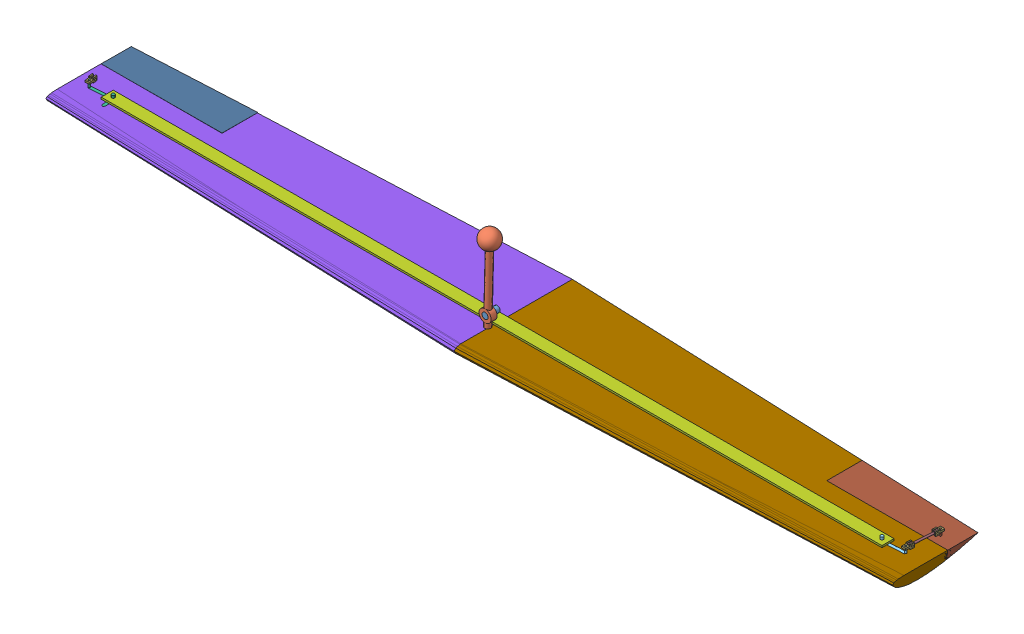
SolidWorks assembly ilk montaj, configuration Varsayılan. Lengths in mm.
Overall size (1400.06 167.48 195.35).
16 component instances, 13 part files, 37 mates.
Components (placement in the parent):
- 1 parça-1: 1 parça [Varsayılan] at (-40.5171 -15.683 10) size (10 10 20)
- ağırlık-1: ağırlık [Varsayılan] at (-40.5171 -15.683 20) x (-0.999712 0.024004 0) z (0 0 1) size (30 159 30)
- acrefour parça-1: acrefour parça [Varsayılan] at (-60.7392 -45.724 23.5) x (-0.999997 -0.002545 0) z (0 0 1) size (50 6 9)
- kanat uzatma-1: kanat uzatma [Varsayılan] at (-70.2401 -44.5815 25) x (0 0 -1) z (0.999997 0.002545 0) size (7 7 620)
- kanat uzatma-2: kanat uzatma [Varsayılan] at (-12.2403 -44.4339 25) x (0 0 1) z (-0.999997 -0.002545 0) size (7 7 620)
- sağ L-1: sağ L [Varsayılan] at (571.2051 -32.1155 16.2863) x (0.998401 0.002541 -0.05647) z (0.002545 -0.999997 0) size (41.5 21.5 23)
- sol L-1: sol L [Varsayılan] at (-694.806 -35.3378 16.0044) x (0.998401 0.002541 -0.05647) z (0.002545 -0.999997 0) size (41.5 21.5 23)
- baz-1: baz [Varsayılan] at (-442.2566 -34.695 7.4933) x (0.999997 0.002545 0) z (-0.002545 0.999997 0) size (1291 20 5)
- sol kanat-1: sol kanat [Varsayılan] at (-38.6126 -72.1334 -489.2786) x (0 0 -1) z (-0.999997 -0.002545 0) size (195.35 23.39 700)
- sağ kanat-1: sağ kanat [Varsayılan] at (-58.6125 -72.1843 -489.2786) x (0 0 -1) z (-0.999997 -0.002545 0) size (195.35 25.39 700)
- sol kanatçık-1: sol kanatçık [Varsayılan] at (-38.6061 -74.6549 -489.092) x (0.000014 -0.00553 -0.999985) z (-0.999997 -0.002545 0) size (65.41 14.06 200)
- sağ kanatçık-1: sağ kanatçık [Varsayılan] at (-58.6125 -72.1843 -489.2786) x (0 0 -1) z (-0.999997 -0.002545 0) size (64.34 23.76 200)
- 2 eksen bağlatı-1: 2 eksen bağlatı [Varsayılan] at (-715.2174 -28.3897 9.6111) x (0.990564 0.002521 -0.137026) z (-0.002545 0.999997 0) size (7 14 7)
- 2 eksen bağlatı-2: 2 eksen bağlatı [Varsayılan] at (630.6659 -24.9641 5.3754) x (0.997747 0.00254 0.067045) z (-0.002545 0.999997 0) size (7 14 7)
- kanatçık aparat-1: kanatçık aparat [Varsayılan] at (697.247 -23.2947 -1002.9291) x (0.002545 -0.999997 0) z (0.067045 0.000171 -0.99775) size (5 3 46.75)
- 2 eksen bağlatı-3: 2 eksen bağlatı [Varsayılan] at (634.2619 -21.955 -48.2536) x (0.997747 0.00254 0.067045) z (0.002545 -0.999997 0) size (7 14 7)
Mates (geometry in assembly coordinates):
- Eş Merkezli1: concentric aligned: circle of 1 parça-1; circle of ağırlık-1
- Çakışık1: coincident aligned: plane of 1 parça-1 through (-40.5171 -15.683 30) normal (0 0 1); plane of ağırlık-1 through (-40.5171 -15.683 30) normal (0 0 1)
- Eş Merkezli2: concentric anti-aligned: circle of ağırlık-1; circle of acrefour parça-1
- Çakışık2: coincident anti-aligned: plane of ağırlık-1 through (-35.519 -40.8102 26.5) normal (0 0 -1); plane of acrefour parça-1 through (-60.7392 -45.724 26.5) normal (0 0 1)
- Eş Merkezli3: concentric anti-aligned: circle of acrefour parça-1; circle of kanat uzatma-1
- Çakışık7: coincident anti-aligned: plane of acrefour parça-1 through (-60.7392 -45.724 26.5) normal (0 0 1); plane of kanat uzatma-1 through (-69.246 -42.2456 26.5) normal (0 0 -1)
- Eş Merkezli4: concentric aligned: circle of acrefour parça-1; circle of kanat uzatma-2
- Çakışık8: coincident anti-aligned: plane of acrefour parça-1 through (-60.7392 -45.724 26.5) normal (0 0 1); plane of kanat uzatma-2 through (-13.2462 -42.1031 26.5) normal (0 0 -1)
- Eş Merkezli7: concentric anti-aligned: circle of kanat uzatma-2; circle of sağ L-1
- Eş Merkezli8: concentric aligned: circle of kanat uzatma-1; circle of sol L-1
- Eş Merkezli9: concentric anti-aligned: circle of sağ L-1; circle of baz-1
- Çakışık11: coincident anti-aligned: plane of sağ L-1 through (571.2051 -32.1155 16.2863) normal (-0.002545 0.999997 0); plane of baz-1 through (-442.2566 -34.695 7.4933) normal (0.002545 -0.999997 0)
- Eş Merkezli10: concentric aligned: circle of sol L-1; circle of baz-1
- Çakışık12: coincident anti-aligned: plane of sol L-1 through (-694.806 -35.3378 16.0044) normal (-0.002545 0.999997 0); plane of baz-1 through (-442.2566 -34.695 7.4933) normal (0.002545 -0.999997 0)
- Çakışık13: coincident aligned: plane of kanat uzatma-1 through (-680.2326 -48.3008 22.4998) normal (0.002545 -0.999997 0); plane of sol L-1 through (-676.7326 -48.2918 25) normal (0.002545 -0.999997 0)
- Çakışık14: coincident aligned: plane of kanat uzatma-2 through (597.7633 -45.0479 27.5002) normal (0.002545 -0.999997 0); plane of sağ L-1 through (594.2633 -45.0568 25) normal (0.002545 -0.999997 0)
- Çakışık15: coincident anti-aligned: plane of sol kanat-1 through (-38.6126 -72.1334 -489.2786) normal (0.999997 0.002545 0); plane of sağ kanat-1 through (-38.6126 -72.1334 -489.2786) normal (-0.999997 -0.002545 0)
- Çakışık16: coincident: point of sol kanat-1; point of sağ kanat-1
- Çakışık17: coincident: point of sol kanat-1; point of sağ kanat-1
- Çakışık18: coincident: point of sol kanat-1; point of sağ kanat-1
- Paralel1: parallel aligned: plane of sol kanat-1 through (2.2894 -33.5635 124.7877) normal (-0.002545 0.999997 0); plane of sağ kanat-1 through (-108.7102 -33.846 -137.851) normal (-0.002545 0.999997 0)
- Eş Merkezli11: concentric aligned: circle of sol kanat-1; circle of sol kanatçık-1
- Çakışık19: coincident aligned: plane of sol kanat-1 through (-738.6103 -73.9151 -489.2786) normal (-0.999997 -0.002545 0); plane of sol kanatçık-1 through (-738.6039 -76.4366 -489.092) normal (-0.999997 -0.002545 0)
- Eş Merkezli12: concentric anti-aligned: circle of sağ kanat-1; circle of sağ kanatçık-1
- Çakışık20: coincident aligned: plane of sağ kanat-1 through (661.3852 -70.3518 -489.2786) normal (0.999997 0.002545 0); plane of sağ kanatçık-1 through (661.3852 -70.3518 -489.2786) normal (0.999997 0.002545 0)
- Çakışık26: coincident anti-aligned: plane of baz-1 through (-38.7054 -35.6679 17.4933) normal (0.999997 0.002545 0); plane of sağ kanat-1 through (-38.6126 -72.1334 -489.2786) normal (-0.999997 -0.002545 0)
- Çakışık27: coincident aligned: plane of baz-1 through (-687.7635 -32.3199 17.4933) normal (0 0 1); plane of sağ kanat-1 through (-38.7156 -31.6679 17.4933) normal (0 0 1)
- Çakışık28: coincident anti-aligned: plane of baz-1 through (-442.2566 -34.695 7.4933) normal (0.002545 -0.999997 0); plane of sağ kanat-1 through (-108.7102 -33.846 -137.851) normal (-0.002545 0.999997 0)
- Eş Merkezli13: concentric aligned: circle of sol L-1; circle of 2 eksen bağlatı-1
- Çakışık29: coincident aligned: plane of sol L-1 through (-715.225 -25.3897 9.6111) normal (-0.002545 0.999997 0); plane of 2 eksen bağlatı-1 through (-715.225 -25.3897 9.6111) normal (-0.002545 0.999997 0)
- Eş Merkezli14: concentric aligned: circle of sağ L-1; circle of 2 eksen bağlatı-2
- Çakışık30: coincident aligned: plane of sağ L-1 through (630.6582 -21.9641 5.3754) normal (-0.002545 0.999997 0); plane of 2 eksen bağlatı-2 through (630.6582 -21.9641 5.3754) normal (-0.002545 0.999997 0)
- Eş Merkezli15: concentric aligned: cylinder of 2 eksen bağlatı-2; cylinder of kanatçık aparat-1 through (622.6505 -23.4845 -2.1787) axis (0.997747 0.00254 0.067045) radius 1.5
- Çakışık31: coincident anti-aligned: plane of 2 eksen bağlatı-2 through (632.8665 -24.9585 -5.0004) normal (-0.997747 -0.00254 -0.067045); plane of kanatçık aparat-1 through (632.3997 -25.96 1.9839) normal (0.997747 0.00254 0.067045)
- Eş Merkezli18: concentric anti-aligned: circle of kanatçık aparat-1; circle of 2 eksen bağlatı-3
- Çakışık39: coincident anti-aligned: plane of kanatçık aparat-1 through (632.5408 -25.9596 -44.8621) normal (-0.997747 -0.00254 -0.067045); plane of 2 eksen bağlatı-3 through (632.0613 -21.9606 -37.8778) normal (0.997747 0.00254 0.067045)
- Çakışık40: coincident anti-aligned: circle of sağ kanatçık-1; circle of 2 eksen bağlatı-3
